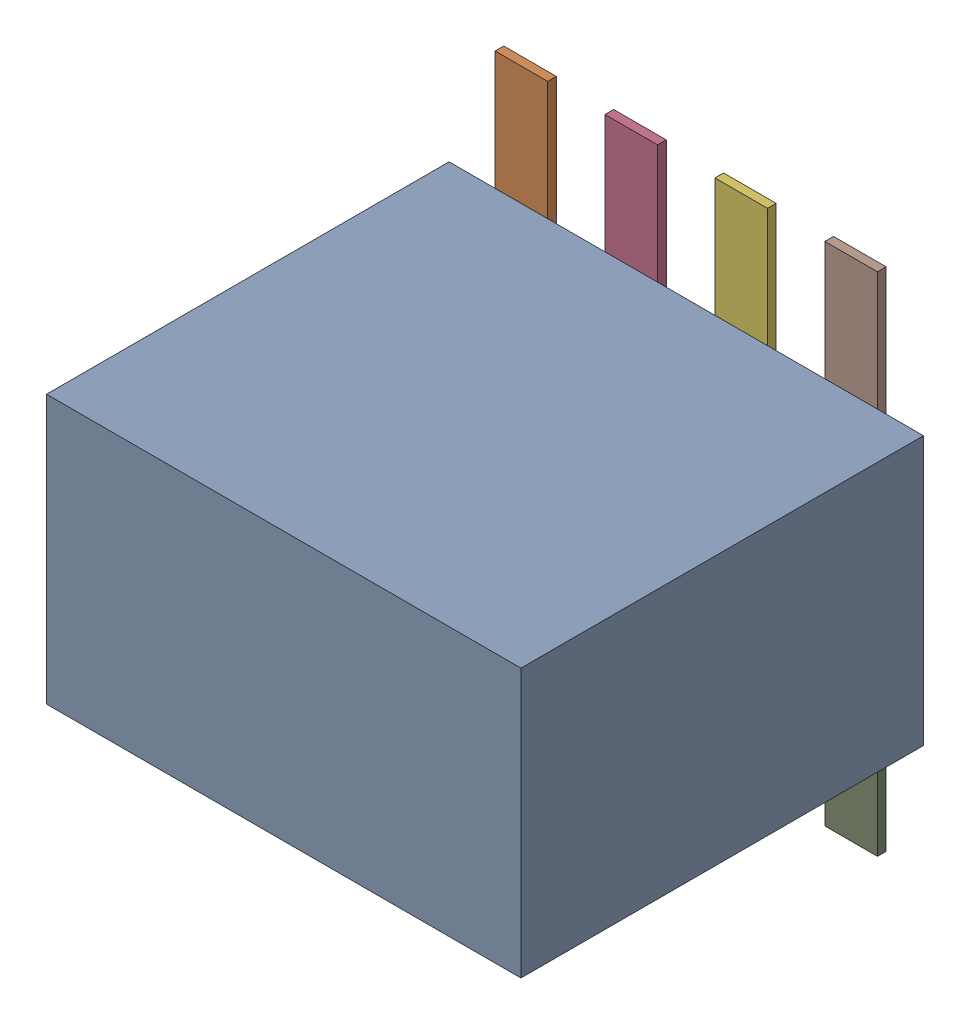
SolidWorks assembly 9452611696_1.step, configuration Default. Lengths in mm.
Overall size (5.48 5.85 4.75).
2 component instances, 2 part files, 0 mates.
Components (placement in the parent):
- Body_2.step-3: Body_2.step [Default] at (0 0 0.1) size (5.48 3.1 4.65)
- Pins_1.step-3: Pins_1.step [Default] at origin size (4.42 5.85 0.1)
